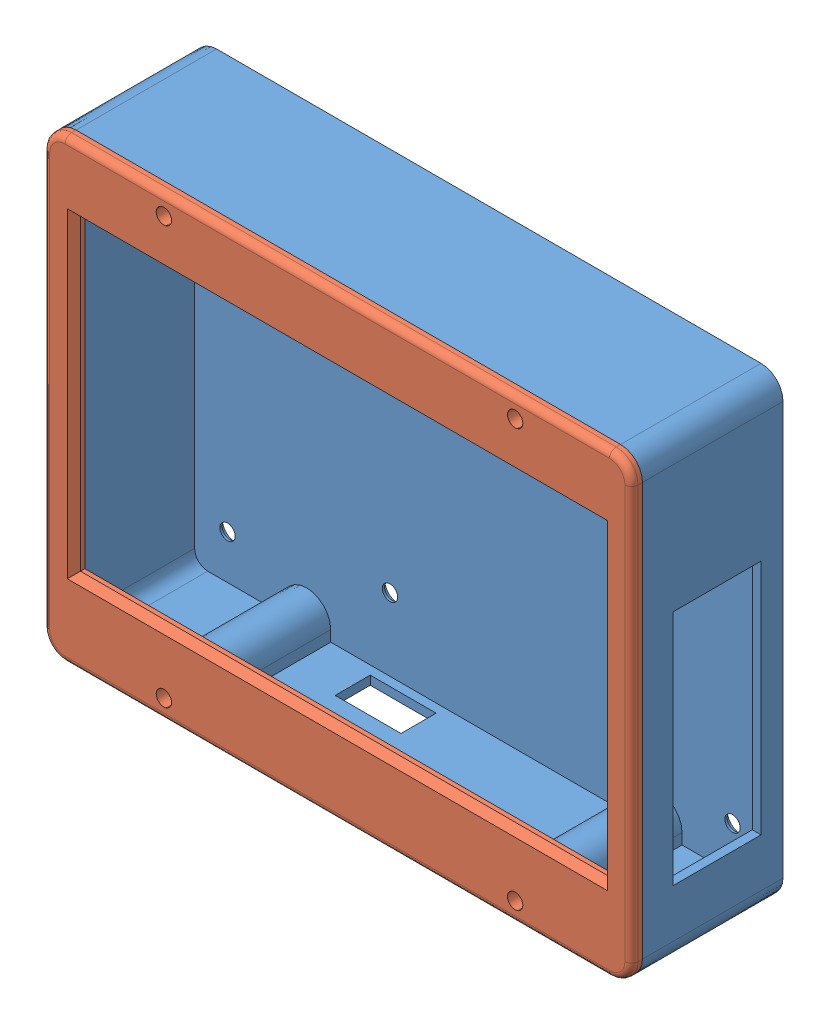
SolidWorks assembly Assemblage1, configuration Défaut. Lengths in mm.
Overall size (134 104 34.5).
2 component instances, 2 part files, 4 mates.
Components (placement in the parent):
- boite-1: boite [Défaut] at (-62.9585 -51.9139 118) size (134 104 32)
- Pièce2^Assemblage1-1: Pièce2^Assemblage1 [Défaut] at (-62.9585 -51.9139 150) size (134 104 2.5) (virtual)
Mates (geometry in assembly coordinates):
- Sur place1: in place: plane of boite-1 through (-62.9585 -51.9139 150) normal (0 0 1); plane of ? through (0 0 150) normal (0 0 1); moOrthogonalPlaneRef_w of boite-1 through (-62.9585 -51.9139 150) normal (0 0 1); plane of ? through (0 0 150) normal (0 1 0); plane of boite-1 through (-62.9585 -51.9139 150) normal (0 0 1); plane of ? through (0 0 150) normal (1 0 0); plane of boite-1 through (-62.9585 -51.9139 150) normal (0 0 1); unknown of Pièce2^Assemblage1-1
- Coïncidente1: coincident aligned: plane of boite-1; plane of Pièce2^Assemblage1-1
- Coïncidente2: coincident aligned: moOrthogonalPlaneRef_w of boite-1 through (-62.9585 -51.9139 150) normal (0 1 0); plane of Pièce2^Assemblage1-1 through (-62.9585 -51.9139 150) normal (0 1 0)
- Coïncidente3: coincident anti-aligned: moOrthogonalPlaneRef_w of boite-1 through (-62.9585 -51.9139 150) normal (-1 0 0); plane of Pièce2^Assemblage1-1 through (-62.9585 -51.9139 150) normal (1 0 0)
